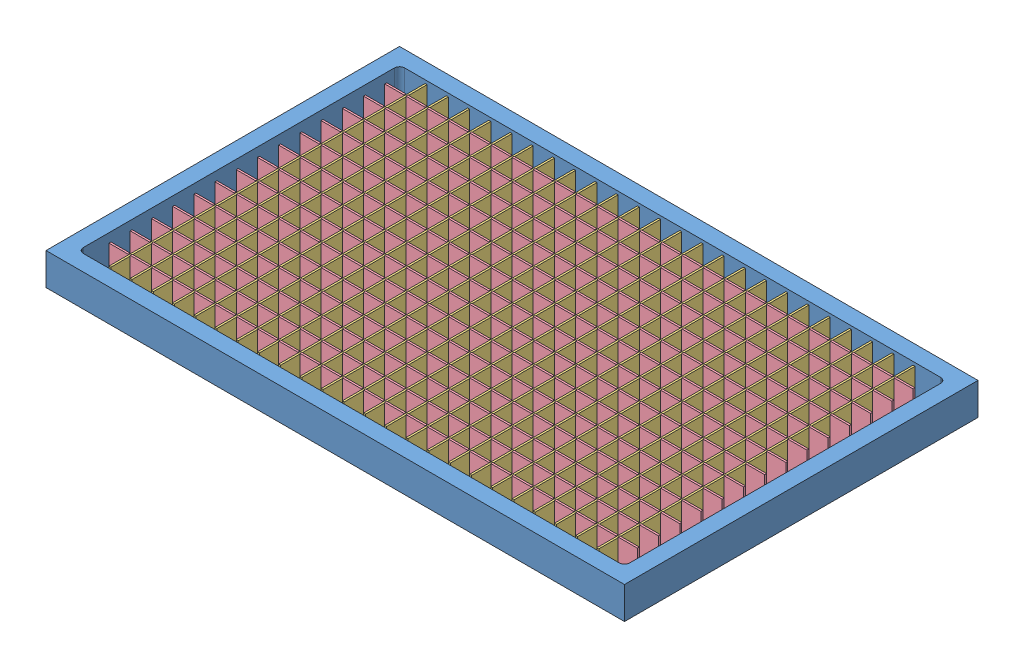
SolidWorks assembly groovegrid_lack_without_foot, configuration Standard. Lengths in mm.
Overall size (900 50 550).
55 component instances, 5 part files, 15 mates.
Components (placement in the parent):
- groovegrid_lack_table_large-1: groovegrid_lack_table_large [Standard] at origin size (900 50 550)
- groovegrid_lack_led_large-1: groovegrid_lack_led_large [Standard] at (0 3 -231) size (825 2.2 10)
- groovegrid_lack_led_large-2: groovegrid_lack_led_large [Standard] at (0 3 -198) size (825 2.2 10)
- groovegrid_lack_led_large-3: groovegrid_lack_led_large [Standard] at (0 3 -165) size (825 2.2 10)
- groovegrid_lack_led_large-4: groovegrid_lack_led_large [Standard] at (0 3 -132) size (825 2.2 10)
- groovegrid_lack_led_large-5: groovegrid_lack_led_large [Standard] at (0 3 -99) size (825 2.2 10)
- groovegrid_lack_led_large-6: groovegrid_lack_led_large [Standard] at (0 3 -66) size (825 2.2 10)
- groovegrid_lack_led_large-7: groovegrid_lack_led_large [Standard] at (0 3 -33) size (825 2.2 10)
- groovegrid_lack_led_large-8: groovegrid_lack_led_large [Standard] at (0 3 0) size (825 2.2 10)
- groovegrid_lack_led_large-9: groovegrid_lack_led_large [Standard] at (0 3 33) size (825 2.2 10)
- groovegrid_lack_led_large-10: groovegrid_lack_led_large [Standard] at (0 3 66) size (825 2.2 10)
- groovegrid_lack_led_large-11: groovegrid_lack_led_large [Standard] at (0 3 99) size (825 2.2 10)
- groovegrid_lack_led_large-12: groovegrid_lack_led_large [Standard] at (0 3 132) size (825 2.2 10)
- groovegrid_lack_led_large-13: groovegrid_lack_led_large [Standard] at (0 3 165) size (825 2.2 10)
- groovegrid_lack_led_large-14: groovegrid_lack_led_large [Standard] at (0 3 198) size (825 2.2 10)
- groovegrid_lack_led_large-15: groovegrid_lack_led_large [Standard] at (0 3 231) size (825 2.2 10)
- groovegrid_lack_sep1_large-1: groovegrid_lack_sep1_large [Standard] at (-378 26.5 0) x (0 0 1) z (-1 0 0) size (492 45 3)
- groovegrid_lack_sep1_large-2: groovegrid_lack_sep1_large [Standard] at (-345 26.5 0) x (0 0 1) z (-1 0 0) size (492 45 3)
- groovegrid_lack_sep1_large-3: groovegrid_lack_sep1_large [Standard] at (-312 26.5 0) x (0 0 1) z (-1 0 0) size (492 45 3)
- groovegrid_lack_sep1_large-4: groovegrid_lack_sep1_large [Standard] at (-279 26.5 0) x (0 0 1) z (-1 0 0) size (492 45 3)
- groovegrid_lack_sep1_large-5: groovegrid_lack_sep1_large [Standard] at (-246 26.5 0) x (0 0 1) z (-1 0 0) size (492 45 3)
- groovegrid_lack_sep1_large-6: groovegrid_lack_sep1_large [Standard] at (-213 26.5 0) x (0 0 1) z (-1 0 0) size (492 45 3)
- groovegrid_lack_sep1_large-7: groovegrid_lack_sep1_large [Standard] at (-180 26.5 0) x (0 0 1) z (-1 0 0) size (492 45 3)
- groovegrid_lack_sep1_large-8: groovegrid_lack_sep1_large [Standard] at (-147 26.5 0) x (0 0 1) z (-1 0 0) size (492 45 3)
- groovegrid_lack_sep1_large-9: groovegrid_lack_sep1_large [Standard] at (-114 26.5 0) x (0 0 1) z (-1 0 0) size (492 45 3)
- groovegrid_lack_sep1_large-10: groovegrid_lack_sep1_large [Standard] at (-81 26.5 0) x (0 0 1) z (-1 0 0) size (492 45 3)
- groovegrid_lack_sep1_large-11: groovegrid_lack_sep1_large [Standard] at (-48 26.5 0) x (0 0 1) z (-1 0 0) size (492 45 3)
- groovegrid_lack_sep1_large-12: groovegrid_lack_sep1_large [Standard] at (-15 26.5 0) x (0 0 1) z (-1 0 0) size (492 45 3)
- groovegrid_lack_sep1_large-13: groovegrid_lack_sep1_large [Standard] at (18 26.5 0) x (0 0 1) z (-1 0 0) size (492 45 3)
- groovegrid_lack_sep1_large-14: groovegrid_lack_sep1_large [Standard] at (51 26.5 0) x (0 0 1) z (-1 0 0) size (492 45 3)
- groovegrid_lack_sep1_large-15: groovegrid_lack_sep1_large [Standard] at (84 26.5 0) x (0 0 1) z (-1 0 0) size (492 45 3)
- groovegrid_lack_sep1_large-16: groovegrid_lack_sep1_large [Standard] at (117 26.5 0) x (0 0 1) z (-1 0 0) size (492 45 3)
- groovegrid_lack_sep1_large-17: groovegrid_lack_sep1_large [Standard] at (150 26.5 0) x (0 0 1) z (-1 0 0) size (492 45 3)
- groovegrid_lack_sep1_large-18: groovegrid_lack_sep1_large [Standard] at (183 26.5 0) x (0 0 1) z (-1 0 0) size (492 45 3)
- groovegrid_lack_sep1_large-19: groovegrid_lack_sep1_large [Standard] at (216 26.5 0) x (0 0 1) z (-1 0 0) size (492 45 3)
- groovegrid_lack_sep1_large-20: groovegrid_lack_sep1_large [Standard] at (249 26.5 0) x (0 0 1) z (-1 0 0) size (492 45 3)
- groovegrid_lack_sep1_large-21: groovegrid_lack_sep1_large [Standard] at (282 26.5 0) x (0 0 1) z (-1 0 0) size (492 45 3)
- groovegrid_lack_sep1_large-22: groovegrid_lack_sep1_large [Standard] at (315 26.5 0) x (0 0 1) z (-1 0 0) size (492 45 3)
- groovegrid_lack_sep1_large-23: groovegrid_lack_sep1_large [Standard] at (348 26.5 0) x (0 0 1) z (-1 0 0) size (492 45 3)
- groovegrid_lack_sep1_large-24: groovegrid_lack_sep1_large [Standard] at (381 26.5 0) x (0 0 1) z (-1 0 0) size (492 45 3)
- groovegrid_lack_sep2_large-1: groovegrid_lack_sep2_large [Standard] at (0 26.5 -213) x (1 0 0) z (0 0 -1) size (822 47 3)
- groovegrid_lack_sep2_large-2: groovegrid_lack_sep2_large [Standard] at (0 26.5 -180) x (1 0 0) z (0 0 -1) size (822 47 3)
- groovegrid_lack_sep2_large-3: groovegrid_lack_sep2_large [Standard] at (0 26.5 -147) x (1 0 0) z (0 0 -1) size (822 47 3)
- groovegrid_lack_sep2_large-4: groovegrid_lack_sep2_large [Standard] at (0 26.5 -114) x (1 0 0) z (0 0 -1) size (822 47 3)
- groovegrid_lack_sep2_large-5: groovegrid_lack_sep2_large [Standard] at (0 26.5 -81) x (1 0 0) z (0 0 -1) size (822 47 3)
- groovegrid_lack_sep2_large-6: groovegrid_lack_sep2_large [Standard] at (0 26.5 -48) x (1 0 0) z (0 0 -1) size (822 47 3)
- groovegrid_lack_sep2_large-7: groovegrid_lack_sep2_large [Standard] at (0 26.5 -15) x (1 0 0) z (0 0 -1) size (822 47 3)
- groovegrid_lack_sep2_large-8: groovegrid_lack_sep2_large [Standard] at (0 26.5 18) x (1 0 0) z (0 0 -1) size (822 47 3)
- groovegrid_lack_sep2_large-9: groovegrid_lack_sep2_large [Standard] at (0 26.5 51) x (1 0 0) z (0 0 -1) size (822 47 3)
- groovegrid_lack_sep2_large-10: groovegrid_lack_sep2_large [Standard] at (0 26.5 84) x (1 0 0) z (0 0 -1) size (822 47 3)
- groovegrid_lack_sep2_large-11: groovegrid_lack_sep2_large [Standard] at (0 26.5 117) x (1 0 0) z (0 0 -1) size (822 47 3)
- groovegrid_lack_sep2_large-12: groovegrid_lack_sep2_large [Standard] at (0 26.5 150) x (1 0 0) z (0 0 -1) size (822 47 3)
- groovegrid_lack_sep2_large-13: groovegrid_lack_sep2_large [Standard] at (0 26.5 183) x (1 0 0) z (0 0 -1) size (822 47 3)
- groovegrid_lack_sep2_large-14: groovegrid_lack_sep2_large [Standard] at (0 26.5 216) x (1 0 0) z (0 0 -1) size (822 47 3)
- groovegrid_lack_pcb_large-1: groovegrid_lack_pcb_large [Standard] at (424 21 -122.6482) x (0 0 1) z (0 -1 0) size (190 1.6 30)
Mates (geometry in assembly coordinates):
- Coincident4: coincident: plane of groovegrid_lack_table_large-1 through (0 3 0) normal (0 1 0); plane of groovegrid_lack_led_large-1 through (0 3 -231) normal (0 -1 0)
- Parallel1: parallel: line of groovegrid_lack_table_large-1 through (-417 3 -250) axis (1 0 0); line of groovegrid_lack_led_large-1 through (412.5 3 -236) axis (-1 0 0)
- Coincident6: coincident: moEndPointRef_w of groovegrid_lack_led_large-1; plane of assembly
- Distance1: distance = 14 mm: line of groovegrid_lack_table_large-1 through (-417 3 -250) axis (1 0 0); line of groovegrid_lack_led_large-1 through (412.5 3 -236) axis (-1 0 0)
- Parallel3: parallel: plane of groovegrid_lack_sep1_large-1 through (-381 26.5 0) normal (-1 0 0); plane of assembly through (0 0 0) normal (1 0 0)
- Coincident12: coincident: moEndPointRef_w of groovegrid_lack_sep1_large-1; plane of assembly
- Coincident14: coincident: moEndPointRef_w of groovegrid_lack_sep2_large-1; plane of assembly
- Coincident15: coincident: plane of groovegrid_lack_table_large-1 through (0 3 0) normal (0 1 0); plane of groovegrid_lack_sep2_large-1 through (-411 3 -216) normal (0 -1 0)
- Parallel4: parallel: line of groovegrid_lack_sep2_large-1 through (411 3 -213) axis (-1 0 0); plane of assembly
- Distance3: distance = 30 mm: line of groovegrid_lack_sep1_large-17 through (147 49 -246) axis (0 -1 0); line of groovegrid_lack_sep2_large-1 through (147 50 -216) axis (0 -1 0)
- Coincident20: coincident: plane of groovegrid_lack_led_large-1 through (0 4 -231) normal (0 1 0); plane of groovegrid_lack_sep1_large-1 through (-381 4 -246) normal (0 -1 0)
- Distance4: distance = 1 mm: plane of groovegrid_lack_pcb_large-1 through (424 21 -122.6482) normal (1 0 0); plane of groovegrid_lack_table_large-1 through (425 3 250) normal (-1 0 0)
- Parallel9: parallel: line of groovegrid_lack_table_large-1 through (425 50 242) axis (0 0 -1); line of groovegrid_lack_pcb_large-1 through (424 36 -27.6482) axis (0 0 -1)
- Distance6: distance = 3 mm: plane of groovegrid_lack_pcb_large-1 through (422.4 6 -217.6482) normal (0 -1 0); plane of groovegrid_lack_table_large-1 through (0 3 0) normal (0 1 0)
- Coincident26: coincident: plane of groovegrid_lack_sep1_large-1 through (-381 26.5 0) normal (-1 0 0); plane of groovegrid_lack_sep2_large-4 through (-381 50 -114) normal (1 0 0)
